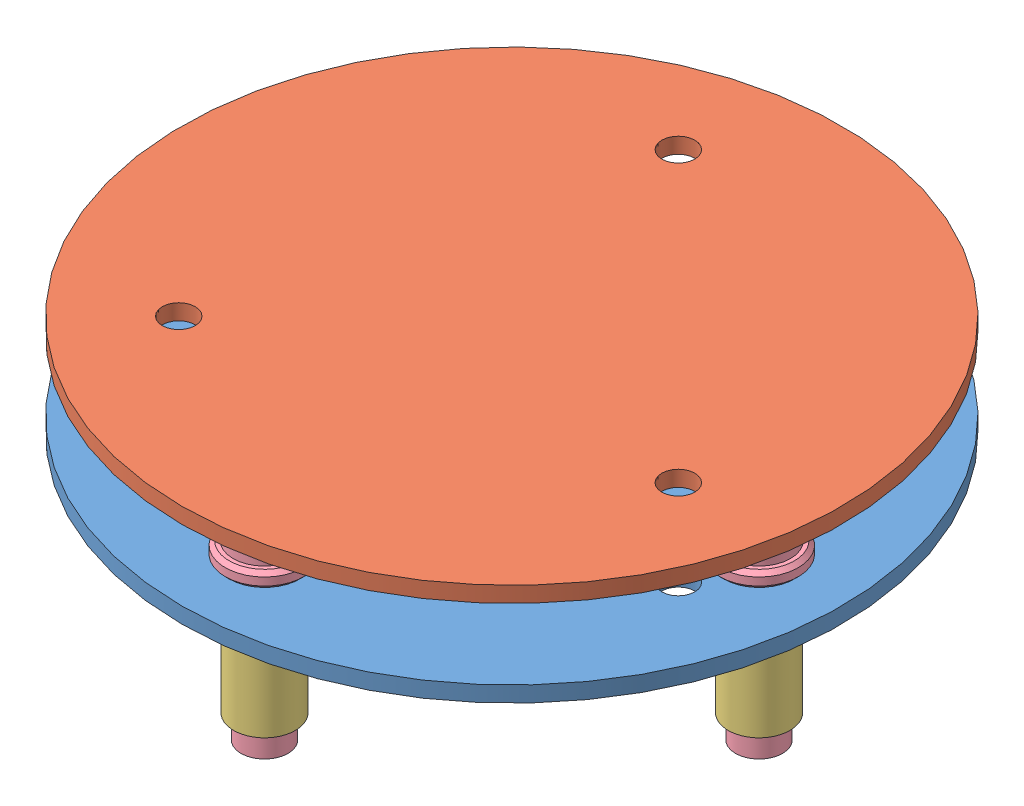
SolidWorks assembly Assem1, configuration ﾃﾞﾌｫﾙﾄ. Lengths in mm.
Overall size (84 31 84).
10 component instances, 4 part files, 24 mates.
Components (placement in the parent):
- plate2_part-1: plate2_part [ﾃﾞﾌｫﾙﾄ] at (-3.6605 -1.9346 84) size (84 2 84)
- plate3_part-1: plate3_part [ﾃﾞﾌｫﾙﾄ] at (-3.6605 9.0654 84) size (84 2 84)
- spacer-1: spacer [ﾃﾞﾌｫﾙﾄ] at (-3.6605 -16.9346 52.5) size (7.85 15 7.85)
- spacer-2: spacer [ﾃﾞﾌｫﾙﾄ] at (27.8395 -16.9346 84) size (7.85 15 7.85)
- spacer-3: spacer [ﾃﾞﾌｫﾙﾄ] at (-3.6605 -16.9346 115.5) size (7.85 15 7.85)
- bolt-1: bolt [ﾃﾞﾌｫﾙﾄ] at (-3.6605 4.5654 52.5) size (10 29 10)
- bolt-2: bolt [ﾃﾞﾌｫﾙﾄ] at (27.8395 4.5654 84) size (10 29 10)
- bolt-3: bolt [ﾃﾞﾌｫﾙﾄ] at (-3.6605 4.5654 115.5) size (10 29 10)
- bolt-4: bolt [ﾃﾞﾌｫﾙﾄ] at (-35.1605 4.5654 84) size (10 29 10)
- spacer-4: spacer [ﾃﾞﾌｫﾙﾄ] at (-35.1605 -16.9346 84) size (7.85 15 7.85)
Mates (geometry in assembly coordinates):
- 同心円1: concentric: cylinder of plate2_part-1 through (-11.425 -1.9346 55.0222) axis (0 1 0) radius 2.1; cylinder of plate3_part-1 through (-11.425 9.0654 55.0222) axis (0 1 0) radius 2.1
- 同心円2: concentric: cylinder of plate2_part-1 through (-24.8737 -1.9346 105.2132) axis (0 1 0) radius 2.1; cylinder of plate3_part-1 through (-24.8737 9.0654 105.2132) axis (0 1 0) radius 2.1
- 同心円3: concentric: cylinder of plate2_part-1 through (25.3173 -1.9346 91.7646) axis (0 1 0) radius 2.1; cylinder of plate3_part-1 through (25.3173 9.0654 91.7646) axis (0 1 0) radius 2.1
- 同心円4: concentric: cylinder of plate2_part-1 through (27.8395 -1.9346 84) axis (0 1 0) radius 3; cylinder of bolt-2 through (27.8395 -19.9346 84) axis (0 1 0) radius 3
- 同心円5: concentric: cylinder of plate2_part-1 through (-3.6605 -1.9346 52.5) axis (0 1 0) radius 3; cylinder of bolt-1 through (-3.6605 -19.9346 52.5) axis (0 1 0) radius 3
- 同心円6: concentric: cylinder of plate2_part-1 through (-3.6605 -1.9346 115.5) axis (0 1 0) radius 3; cylinder of bolt-3 through (-3.6605 -19.9346 115.5) axis (0 1 0) radius 3
- 同心円7: concentric: cylinder of plate2_part-1 through (-35.1605 -1.9346 84) axis (0 1 0) radius 3; cylinder of bolt-4 through (-35.1605 -19.9346 84) axis (0 1 0) radius 3
- 同心円8: concentric: cylinder of bolt-4 through (-35.1605 -19.9346 84) axis (0 1 0) radius 3; cylinder of spacer-4 through (-35.1605 -1.9346 84) axis (0 -1 0) radius 3.1
- 一致1: coincident: plane of plate2_part-1 through (-3.6605 -1.9346 84) normal (0 -1 0); plane of spacer-4 through (-35.1605 -1.9346 84) normal (0 1 0)
- 同心円9: concentric: cylinder of plate2_part-1 through (-35.1605 -1.9346 84) axis (0 1 0) radius 3; cylinder of spacer-4 through (-35.1605 -1.9346 84) axis (0 -1 0) radius 3.1
- 同心円10: concentric: cylinder of plate2_part-1 through (-3.6605 -1.9346 52.5) axis (0 1 0) radius 3; cylinder of spacer-1 through (-3.6605 -1.9346 52.5) axis (0 -1 0) radius 3.1
- 一致2: coincident: plane of plate2_part-1 through (-3.6605 -1.9346 84) normal (0 -1 0); plane of spacer-1 through (-3.6605 -1.9346 52.5) normal (0 1 0)
- 一致3: coincident: plane of plate2_part-1 through (-3.6605 -1.9346 84) normal (0 -1 0); plane of spacer-2 through (27.8395 -1.9346 84) normal (0 1 0)
- 一致4: coincident: plane of plate2_part-1 through (-3.6605 -1.9346 84) normal (0 -1 0); plane of spacer-3 through (-3.6605 -1.9346 115.5) normal (0 1 0)
- 同心円11: concentric: cylinder of plate2_part-1 through (27.8395 -1.9346 84) axis (0 1 0) radius 3; cylinder of spacer-2 through (27.8395 -1.9346 84) axis (0 -1 0) radius 3.1
- 同心円12: concentric: cylinder of plate2_part-1 through (-3.6605 -1.9346 115.5) axis (0 1 0) radius 3; cylinder of spacer-3 through (-3.6605 -1.9346 115.5) axis (0 -1 0) radius 3.1
- 同心円13: concentric: cylinder of spacer-3 through (-3.6605 -1.9346 115.5) axis (0 -1 0) radius 3.1; cylinder of bolt-3 through (-3.6605 -19.9346 115.5) axis (0 1 0) radius 3
- 同心円14: concentric: cylinder of spacer-2 through (27.8395 -1.9346 84) axis (0 -1 0) radius 3.1; cylinder of bolt-2 through (27.8395 -19.9346 84) axis (0 1 0) radius 3
- 同心円15: concentric: cylinder of spacer-1 through (-3.6605 -1.9346 52.5) axis (0 -1 0) radius 3.1; cylinder of bolt-1 through (-3.6605 -19.9346 52.5) axis (0 1 0) radius 3
- 一致5: coincident: plane of plate2_part-1 through (-3.6605 0.0654 84) normal (0 1 0); plane of bolt-2 through (27.8395 0.0654 84) normal (0 -1 0)
- 一致6: coincident: plane of plate2_part-1 through (-3.6605 0.0654 84) normal (0 1 0); plane of bolt-1 through (-3.6605 0.0654 52.5) normal (0 -1 0)
- 一致7: coincident: plane of plate2_part-1 through (-3.6605 0.0654 84) normal (0 1 0); plane of bolt-3 through (-3.6605 0.0654 115.5) normal (0 -1 0)
- 一致8: coincident: plane of plate2_part-1 through (-3.6605 0.0654 84) normal (0 1 0); plane of bolt-4 through (-35.1605 0.0654 84) normal (0 -1 0)
- 一致9: coincident: plane of plate3_part-1 through (-3.6605 9.0654 84) normal (0 -1 0); plane of bolt-1 through (-3.6605 9.0654 52.5) normal (0 1 0); plane of spacer-3
